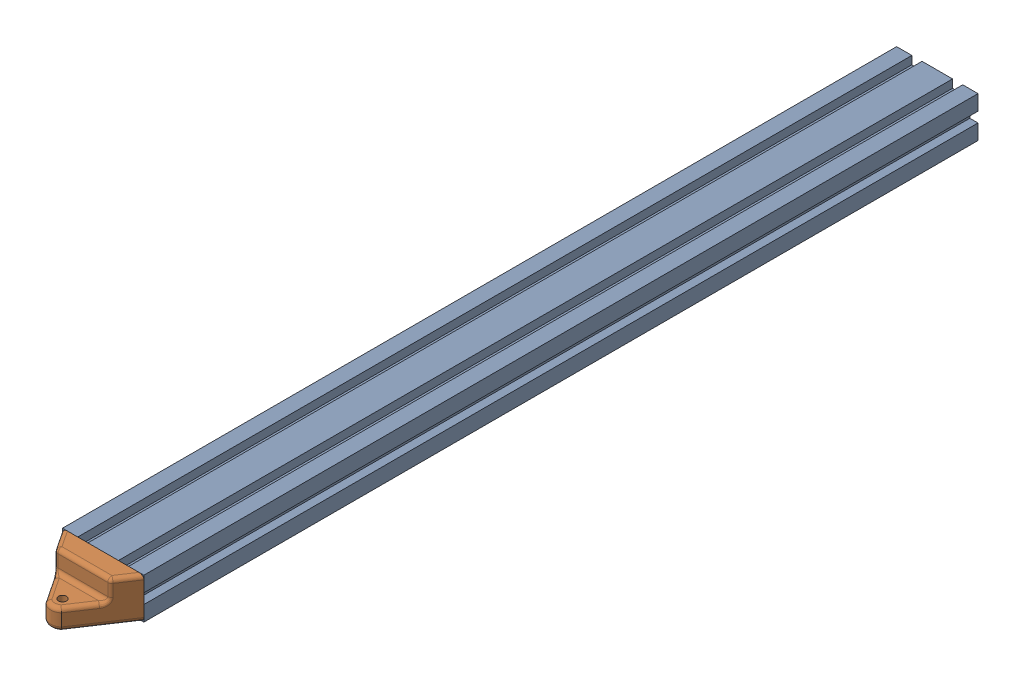
SolidWorks assembly Pivot ar, configuration Défaut. Lengths in mm.
Overall size (40 20.11 435.75).
2 component instances, 2 part files, 11 mates.
Components (placement in the parent):
- profilé 410 20 40 - Copie-1: profilé 410 20 40 - Copie [Défaut] at (-40 -20 -410) size (40 20 410)
- pivot2024-1: pivot2024 [Défaut] at (-40 -20 0) x (0 0 1) z (-1 0 0) size (25.75 20.11 40)
Mates (geometry in assembly coordinates):
- Coïncidente2: coincident aligned: plane of profilé 410 20 40 - Copie-1 through (-40 -20 0) normal (0 0 1)
- Coïncidente3: coincident aligned: plane of profilé 410 20 40 - Copie-1 through (0 -20 0) normal (1 0 0)
- Coïncidente4: coincident aligned: plane of profilé 410 20 40 - Copie-1 through (-40 0 0) normal (0 1 0)
- Coïncidente5: coincident anti-aligned: line of profilé 410 20 40 - Copie-1 through (-27.5 0 0) axis (1 0 0); line of pivot2024-1 through (-2.4037 0 0) axis (-1 0 0)
- Coïncidente6: coincident anti-aligned: line of profilé 410 20 40 - Copie-1 through (-40 -7.5 0) axis (0 1 0); line of pivot2024-1 through (-40 -2 0) axis (0 -1 0)
- Coaxiale1: concentric anti-aligned: cylinder of pivot2024-1 through (-20 -10 20) axis (0 -1 0) radius 2; cylinder of pivot2024-2 through (-20 -10 20) axis (0 1 0) radius 2
- Coïncidente7: coincident anti-aligned: plane of pivot2024-1 through (-40 -10 0) normal (0 1 0); plane of pivot2024-2 through (-35.6235 -10 43.5777) normal (0 -1 0)
- AngleLimite1: limit planar angle = 0.20019 rad anti-aligned: plane of pivot2024-2 through (-35.6235 -10 43.5777) normal (0.198856 0 0.980029); plane of pivot2024-1 through (-40 -10 0) normal (0 0 -1)
- Coïncidente9: coincident anti-aligned: plane of pivot2024-2 through (-35.6235 -10 43.5777) normal (0.198856 0 0.980029); plane of profilé 410 20 40 - Copie-2 through (184.883 -20 -1.1648) normal (-0.198856 0 -0.980029)
- Coïncidente10: coincident: point of pivot2024-2; unknown of profilé 410 20 40 - Copie-2
- Parallèle1: parallel aligned: line of pivot2024-2 through (3.5777 -18 35.6235) axis (0 1 0); line of profilé 410 20 40 - Copie-2 through (184.883 -7.5 -1.1648) axis (0 1 0)
